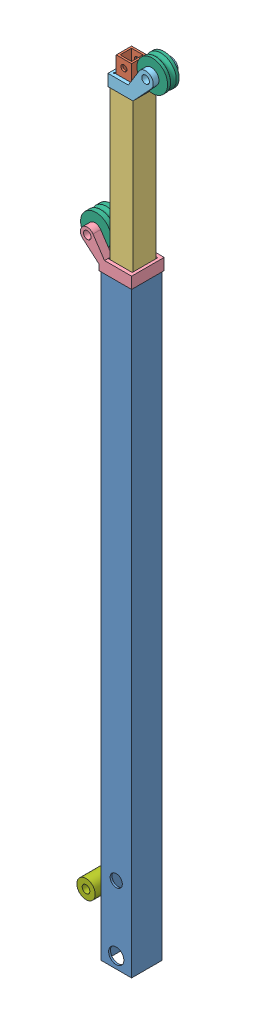
SolidWorks assembly Climber, configuration Default. Lengths in mm.
Overall size (74.32 660.55 26.99).
10 component instances, 9 part files, 26 mates.
Components (placement in the parent):
- Tubes-1: Tubes [Default] at origin size (25.4 501.65 25.4)
- Tubes3-1: Tubes3 [Default] at (0 141.4398 0) size (12.7 508 12.7)
- Tubes2-1: Tubes2 [Default] at (1.0954 138.8998 0) size (19.05 495.3 19.05)
- Cap-1: Cap [Default] at (0 504.19 0) x (-1 0 0) z (0 0 1) size (42.42 26.35 26.99)
- Cap2-1: Cap2 [Default] at (1.0954 636.7398 0) x (-1 0 0) z (0 0 1) size (37.5 26.99 20.64)
- Roller-1: Roller [Default] at (21.9234 647.8523 -4.7942) size (25.4 25.4 9.59)
- Roller-2: Roller [2nd Stage] at (-23.2093 515.3025 -6.3182) x (0.929731 -0.368239 0) z (0 0 1) size (25.4 25.4 12.64)
- Space-1: Space [Default] at (-27.5695 42.3738 -10.16) x (0.713951 -0.700196 0) z (0 0 1) size (15.24 15.24 20.32)
- Part1-1: Part1 [Default] at (2.2782 151.5998 -0.9829) x (1 0 0) z (0 1 0) size (22.12 22.12 25.4)
- Part2-1: Part2 [Default] at (0 154.1398 0) x (0 0 1) z (0 1 0) size (15.96 15.78 25.4)
Mates (geometry in assembly coordinates):
- Coincident11: coincident anti-aligned: plane of Tubes2-1 through (1.0954 634.1998 0) normal (0 1 0); plane of Cap2-1 through (1.0954 634.1998 0) normal (0 -1 0)
- Width13: width anti-aligned: plane of Tubes2-1 through (-8.4296 634.1998 -9.525) normal (0 0 -1); plane of Tubes-1 through (-8.4296 634.1998 9.525) normal (0 0 1); plane of Tubes2-1 through (-11.1125 501.65 -11.1125) normal (0 0 1); plane of Tubes-1 through (-11.1125 501.65 11.1125) normal (0 0 -1)
- Coincident14: coincident aligned: plane of Tubes2-1 through (1.0954 138.8998 0) normal (0 0 1)
- Coincident15: coincident aligned: plane of Tubes-1 through (0 0 0) normal (0 0 1)
- Coincident16: coincident aligned: plane of Tubes-1 through (0 0 0) normal (1 0 0)
- Coincident17: coincident aligned: plane of Tubes-1 through (0 0 0) normal (0 1 0)
- Coincident18: coincident aligned: plane of Tubes3-1 through (0 141.4398 0) normal (0 0 1)
- Coincident19: coincident aligned: plane of Tubes3-1 through (0 141.4398 0) normal (1 0 0)
- Coincident20: coincident aligned: plane of Tubes2-1 through (1.0954 138.8998 0) normal (0 0 1); plane of Cap2-1 through (1.0954 636.7398 0) normal (0 0 1)
- Coincident21: coincident anti-aligned: plane of Tubes2-1 through (1.0954 138.8998 0) normal (1 0 0); plane of Cap2-1 through (1.0954 636.7398 0) normal (-1 0 0)
- LimitDistance1: limit distance = 12.7 mm aligned: plane of Tubes3-1 through (0 649.4398 0) normal (0 1 0); plane of Cap2-1 through (1.0954 636.7398 0) normal (0 1 0)
- Coincident22: coincident aligned: plane of Cap-1 through (0 504.19 0) normal (0 0 1)
- Coincident23: coincident anti-aligned: plane of Tubes-1 through (0 501.65 0) normal (0 1 0); plane of Cap-1 through (0 501.65 0) normal (0 -1 0)
- Coincident24: coincident anti-aligned: plane of Cap-1 through (0 504.19 0) normal (-1 0 0)
- Width18: width aligned: plane of Cap-1 through (-8.9218 501.65 0) normal (1 0 0); plane of Tubes2-1 through (11.1125 501.65 0) normal (-1 0 0); plane of Cap-1 through (10.6204 634.1998 -9.525) normal (1 0 0); plane of Tubes2-1 through (-8.4296 634.1998 -9.525) normal (-1 0 0)
- LimitDistance2: limit distance = 132.5498 mm aligned: plane of Cap2-1 through (1.0954 636.7398 0) normal (0 1 0); plane of Cap-1 through (0 504.19 0) normal (0 1 0)
- Concentric1: concentric anti-aligned: cylinder of Cap2-1 through (21.9234 647.8523 5.5563) axis (0 0 1) radius 3.175; cylinder of Roller-1 through (21.9234 647.8523 4.7942) axis (0 0 -1) radius 3.175
- Width19: width anti-aligned: plane of Roller-1 through (21.9234 647.8523 4.7942) normal (0 0 1); plane of Cap2-1 through (21.9234 647.8523 -4.7942) normal (0 0 -1); plane of Roller-1 through (1.0954 636.7398 5.5563) normal (0 0 -1); plane of Cap2-1 through (21.9234 647.8523 -5.5563) normal (0 0 1)
- Concentric2: concentric aligned: cylinder of Cap-1 through (-23.2093 515.3025 -7.1437) axis (0 0 -1) radius 3.175; cylinder of Roller-2 through (-23.2093 515.3025 6.3182) axis (0 0 -1) radius 3.175
- Width20: width anti-aligned: plane of Roller-2 through (-23.2093 515.3025 -6.3182) normal (0 0 -1); plane of Cap-1 through (-23.2093 515.3025 6.3182) normal (0 0 1); plane of Roller-2 through (-23.2093 515.3025 -7.1437) normal (0 0 1); plane of Cap-1 through (0 504.19 7.1437) normal (0 0 -1)
- Width28: width aligned: plane of Tubes2-1 through (10.6204 634.1998 -9.525) normal (1 0 0); plane of Part1-1 through (-8.4296 634.1998 -9.525) normal (-1 0 0); plane of Tubes2-1 through (-8.4796 164.2998 -9.575) normal (1 0 0); plane of Part1-1 through (10.6704 164.2998 -9.575) normal (-1 0 0)
- Width29: width anti-aligned: plane of Tubes2-1 through (-8.4296 634.1998 9.525) normal (0 0 1); plane of Part1-1 through (-8.4296 634.1998 -9.525) normal (0 0 -1); plane of Tubes2-1 through (-8.4796 164.2998 9.575) normal (0 0 -1); plane of Part1-1 through (-8.4796 164.2998 -9.575) normal (0 0 1)
- Coincident35: coincident aligned: plane of Tubes2-1 through (1.0954 138.8998 0) normal (0 -1 0); plane of Part1-1 through (2.2782 138.8998 -0.9829) normal (0 -1 0)
- Width30: width anti-aligned: plane of Part2-1 through (8.9835 166.8398 7.9775) normal (0 0 1); plane of Tubes3-1 through (8.9835 166.8398 -7.9775) normal (0 0 -1); plane of Part2-1 through (-6.35 649.4398 -6.35) normal (0 0 -1); plane of Tubes3-1 through (-6.35 649.4398 6.35) normal (0 0 1)
- Width32: width aligned: plane of Part2-1 through (-6.4 166.8398 -6.4) normal (1 0 0); plane of Tubes3-1 through (6.4 166.8398 -6.4) normal (-1 0 0); plane of Part2-1 through (6.35 649.4398 -6.35) normal (1 0 0); plane of Tubes3-1 through (-6.35 649.4398 -6.35) normal (-1 0 0)
- Coincident37: coincident aligned: plane of Tubes3-1 through (0 141.4398 0) normal (0 -1 0); plane of Part2-1 through (0 141.4398 0) normal (0 -1 0)
